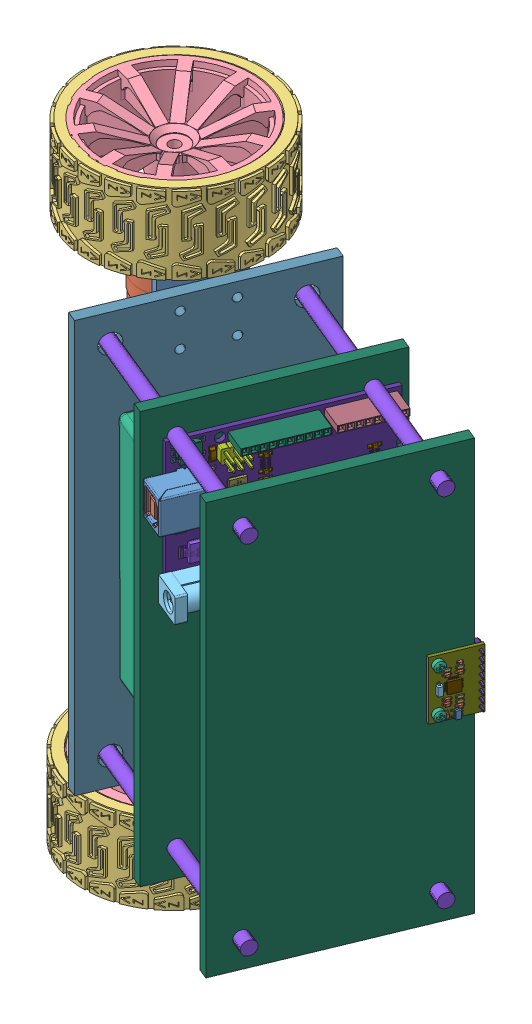
SolidWorks assembly Self-Balancing Robot, configuration Default. Lengths in mm.
Overall size (169.38 227.6 124.57).
147 component instances, 62 part files, 48 mates.
Components (placement in the parent):
- Motor Holder-3: Motor Holder [Default] at (-32.9879 122.7699 -70.1452) x (-0.380878 0 0.924625) z (0.924625 0 0.380878) size (26 33 33)
- Motor-3: Motor [Default] at (-47.7819 117.2699 -76.2392) x (0.924625 0 0.380878) z (0.380878 0 -0.924625) size (25 71 25)
- blue_wheel_with_adapter-1: blue_wheel_with_adapter [Default] at (-11.9395 117.0086 -118.8911) x (-0.932891 0 -0.360158) z (0 1 0) size (69.31 69.31 29.8)
  - 65mm tire-1: 65mm tire [Default] at (18.1044 52.2783 38.5614) x (-0.068419 0.997657 0) z (0 0 1) size (65.01 65.01 29)
  - blue_wheel_frame-2: blue_wheel_frame [Default] at (18.0756 52.6985 38.5614) x (0 0 -1) z (-0.994893 -0.10093 0) size (29 56 56)
  - motor_adapter-1: motor_adapter [Default] at (18.0661 52.7117 35.2614) x (0.583313 -0.812247 0) z (0 0 1) size (13.7 12 18.23)
- blue_wheel_with_adapter-2: blue_wheel_with_adapter [Default] at (-61.4059 -4.4687 -22.2185) x (-0.837844 0 -0.545909) z (0 -1 0) size (69.31 69.31 29.8)
  - 65mm tire-1: 65mm tire [Default] at (18.1044 52.2783 38.5614) x (-0.068419 0.997657 0) z (0 0 1) size (65.01 65.01 29)
  - blue_wheel_frame-2: blue_wheel_frame [Default] at (18.0756 52.6985 38.5614) x (0 0 -1) z (-0.994893 -0.10093 0) size (29 56 56)
  - motor_adapter-1: motor_adapter [Default] at (18.0661 52.7117 35.2614) x (0.583313 -0.812247 0) z (0 0 1) size (13.7 12 18.23)
- Motor-4: Motor [Default] at (-47.7819 -4.7301 -76.2392) x (0.924625 0 0.380878) z (-0.380878 0 0.924625) size (25 71 25)
- Motor Holder-4: Motor Holder [Default] at (-32.9879 -10.2301 -70.1452) x (0.380878 0 -0.924625) z (0.924625 0 0.380878) size (26 33 33)
- Battery-1: Battery [Default] at (-37.8979 90.6926 -146.4677) x (0.0011 -0.999996 -0.002671) z (-0.380877 -0.002889 0.924621) size (88 20.21 59.22)
  - battery_body-1: battery_body [Default] at (33.4598 40.6095 66.8775) size (85 20.21 55)
  - Mini Rocker 4-Pin Switch-1: Mini Rocker 4-Pin Switch [Default] at (67.6398 50.3895 39.3775) x (-1 0 0) z (0 -1 0) size (10.64 14.37 14.84)
  - dc_power_jack_assembly-1: dc_power_jack_assembly [Default] at (66.0649 52.0993 55.8301) x (1 0 0) z (0 0 -1) size (41 11.5 15)
    - main_body-1: main_body [Default] at (-16.1052 -4.2602 1.6818) size (34 11.5 15)
    - green_screw_section-1: green_screw_section [Default] at (-21.1052 -4.2602 6.6818) x (-1 0 0) z (0 0 -1) size (7 10 10)
    - jack_outer_metal-1: jack_outer_metal [Default] at (0.8948 1.4898 1.6818) x (0 0.735968 -0.677016) z (1 0 0) size (7 7 12)
    - jack_inner_rod-1: jack_inner_rod [Default] at (0.8948 1.4898 1.6818) x (0 0 -1) z (1 0 0) size (2.1 2.1 12)
    - wireholder_with_screw_assembly-1: wireholder_with_screw_assembly [Default] at (4.4628 17.1409 -69.445) x (0 0 -1) z (-1 0 0) size (4 9.26 5)
      - wireholder-1: wireholder [Default] at (-75.1268 12.4011 26.568) size (4 5.5 5)
      - pan cross head_ai-1: pan cross head_ai [CR-PHMS 0.06-80x0.125x0.125-N] at (-73.6268 21.1937 29.068) x (0 -1 0) z (0 0 1) size (4.26 2.95 2.95)
    - wireholder_with_screw_assembly-2: wireholder_with_screw_assembly [Default] at (4.4628 17.1409 -74.445) x (0 0 -1) z (-1 0 0) size (4 9.26 5)
      - wireholder-1: wireholder [Default] at (-75.1268 12.4011 26.568) size (4 5.5 5)
      - pan cross head_ai-1: pan cross head_ai [CR-PHMS 0.06-80x0.125x0.125-N] at (-73.6268 21.1937 29.068) x (0 -1 0) z (0 0 1) size (4.26 2.95 2.95)
- Base_0-1: Base_0 [Default] at (-26.5155 56.2699 -67.479) x (0 1 0) z (-0.380878 0 0.924625) size (150 4 75)
- Base_1-1: Base_1 [Default] at (14.168 56.2699 -50.7204) x (0 1 0) z (-0.380878 0 0.924625) size (150 4 75)
- L298N-1: L298N [Default] at (11.1248 21.059 -86.5942) x (0 -1 0) z (-0.380878 0 0.924625) size (39.39 19 41.67)
- Base_1-2: Base_1 [Default] at (54.8515 56.2699 -33.9617) x (0 1 0) z (-0.380878 0 0.924625) size (150 4 75)
- arduino uno.IGS-2: arduino uno.IGS [Default] at (3.8293 67.6059 -21.2898) x (0 -1 0) z (-0.380878 0 0.924625) size (60.05 15.26 75.79)
  - unoboard blue.IGS-1: unoboard blue.IGS [Default] at origin size (53.35 1.66 68.59)
  - 47uf CAP Dcase.IGS-1: 47uf CAP Dcase.IGS [Default] at (-9.4141 0 -18.4991) x (0 0 -1) z (1 0 0) size (7.21 5.88 8.01)
  - 47uf CAP Dcase.IGS-2: 47uf CAP Dcase.IGS [Default] at (-9.4141 0 -25.7132) x (0 0 -1) z (1 0 0) size (7.21 5.88 8.01)
  - USB SHELL.IGS-1: USB SHELL.IGS [Default] at (-38.02 0.43 6.35) size (13.73 15.21 16.52)
  - USB core.IGS-1: USB core.IGS [Default] at (-38.02 0.43 6.35) size (11.31 10.69 15.76)
  - usb top contact.IGS-1: usb top contact.IGS [Default] at (-36.77 6.52 5.97) size (1.01 9.68 13.77)
  - usb top contact.IGS-2: usb top contact.IGS [Default] at (-39.27 6.52 5.97) size (1.01 9.68 13.77)
  - usb btm contact.IGS-1: usb btm contact.IGS [Default] at (-36.77 4.84 5.97) size (1.14 6.85 11.77)
  - usb btm contact.IGS-2: usb btm contact.IGS [Default] at (-39.27 4.84 5.97) size (1.14 6.85 11.77)
  - power jack.IGS-1: power jack.IGS [Default] at (-7.675 0 1.905) size (11.21 15.21 15.91)
  - crystal.IGS-1: crystal.IGS [Default] at (-26.162 0 -18.923) x (1 0 0) z (0 0 -1) size (4.01 5.08 12.71)
  - 2pin_header__02.IGS-1: 2pin_header__02.IGS [Default] at (-46.23 0 -15.75) size (5.01 11.76 2.55)
  - 2pin_header__02.IGS-2: 2pin_header__02.IGS [Default] at (-30.43 0 -64.91) x (0 0 1) z (-1 0 0) size (5.01 11.76 2.55)
  - 2pin_header__02.IGS-3: 2pin_header__02.IGS [Default] at (-27.89 0 -64.91) x (0 0 1) z (-1 0 0) size (5.01 11.76 2.55)
  - 2pin_header__02.IGS-4: 2pin_header__02.IGS [Default] at (-25.35 0 -64.91) x (0 0 1) z (-1 0 0) size (5.01 11.76 2.55)
  - 2pin_header__02.IGS-5: 2pin_header__02.IGS [Default] at (-46.23 0 -18.29) size (5.01 11.76 2.55)
  - 2pin_header__02.IGS-6: 2pin_header__02.IGS [Default] at (-46.23 0 -20.83) size (5.01 11.76 2.55)
  - nano - reg.IGS-1: nano - reg.IGS [Default] at (-17.399 0 -7.747) size (6.51 1.75 8.31)
  - led.IGS-1: led.IGS [Default] at (-34.29 0 -27.94) x (0 0 1) z (-1 0 0) size (4.01 0.86 1.55)
  - led.IGS-2: led.IGS [Default] at (-36.83 0 -27.94) x (0 0 1) z (-1 0 0) size (4.01 0.86 1.55)
  - led.IGS-3: led.IGS [Default] at (-42.037 0 -27.94) x (0 0 1) z (-1 0 0) size (4.01 0.86 1.55)
  - led.IGS-4: led.IGS [Default] at (-36.576 0 -58.42) x (0 0 1) z (-1 0 0) size (4.01 0.86 1.55)
  - dip28.IGS-1: dip28.IGS [Default] at (-16.383 1.5 -46.355) x (0 0 -1) z (1 0 0) size (35.49 2.81 10.11)
  - dip socket pin.IGS-1: dip socket pin.IGS [Default] at (-20.193 4.3 -62.865) x (0 0 -1) z (1 0 0) size (1.71 7.38 1.71)
  - dip socket pin.IGS-2: dip socket pin.IGS [Default] at (-12.573 4.3 -62.865) x (0 0 -1) z (1 0 0) size (1.71 7.38 1.71)
  - dip socket pin.IGS-3: dip socket pin.IGS [Default] at (-20.193 4.3 -60.325) x (0 0 -1) z (1 0 0) size (1.71 7.38 1.71)
  - dip socket pin.IGS-4: dip socket pin.IGS [Default] at (-12.573 4.3 -60.325) x (0 0 -1) z (1 0 0) size (1.71 7.38 1.71)
  - dip socket pin.IGS-5: dip socket pin.IGS [Default] at (-20.193 4.3 -57.785) x (0 0 -1) z (1 0 0) size (1.71 7.38 1.71)
  - dip socket pin.IGS-6: dip socket pin.IGS [Default] at (-12.573 4.3 -57.785) x (0 0 -1) z (1 0 0) size (1.71 7.38 1.71)
  - dip socket pin.IGS-7: dip socket pin.IGS [Default] at (-20.193 4.3 -55.245) x (0 0 -1) z (1 0 0) size (1.71 7.38 1.71)
  - dip socket pin.IGS-8: dip socket pin.IGS [Default] at (-12.573 4.3 -55.245) x (0 0 -1) z (1 0 0) size (1.71 7.38 1.71)
  - dip socket pin.IGS-9: dip socket pin.IGS [Default] at (-20.193 4.3 -52.705) x (0 0 -1) z (1 0 0) size (1.71 7.38 1.71)
  - dip socket pin.IGS-10: dip socket pin.IGS [Default] at (-12.573 4.3 -52.705) x (0 0 -1) z (1 0 0) size (1.71 7.38 1.71)
  - dip socket pin.IGS-11: dip socket pin.IGS [Default] at (-20.193 4.3 -50.165) x (0 0 -1) z (1 0 0) size (1.71 7.38 1.71)
  - dip socket pin.IGS-12: dip socket pin.IGS [Default] at (-12.573 4.3 -50.165) x (0 0 -1) z (1 0 0) size (1.71 7.38 1.71)
  - dip socket pin.IGS-13: dip socket pin.IGS [Default] at (-20.193 4.3 -47.625) x (0 0 -1) z (1 0 0) size (1.71 7.38 1.71)
  - dip socket pin.IGS-14: dip socket pin.IGS [Default] at (-12.573 4.3 -47.625) x (0 0 -1) z (1 0 0) size (1.71 7.38 1.71)
  - dip socket pin.IGS-15: dip socket pin.IGS [Default] at (-20.193 4.3 -45.085) x (0 0 -1) z (1 0 0) size (1.71 7.38 1.71)
  - dip socket pin.IGS-16: dip socket pin.IGS [Default] at (-12.573 4.3 -45.085) x (0 0 -1) z (1 0 0) size (1.71 7.38 1.71)
  - dip socket pin.IGS-17: dip socket pin.IGS [Default] at (-20.193 4.3 -42.545) x (0 0 -1) z (1 0 0) size (1.71 7.38 1.71)
  - dip socket pin.IGS-18: dip socket pin.IGS [Default] at (-12.573 4.3 -42.545) x (0 0 -1) z (1 0 0) size (1.71 7.38 1.71)
  - dip socket pin.IGS-19: dip socket pin.IGS [Default] at (-20.193 4.3 -40.005) x (0 0 -1) z (1 0 0) size (1.71 7.38 1.71)
  - dip socket pin.IGS-20: dip socket pin.IGS [Default] at (-12.573 4.3 -40.005) x (0 0 -1) z (1 0 0) size (1.71 7.38 1.71)
  - dip socket pin.IGS-21: dip socket pin.IGS [Default] at (-20.193 4.3 -37.465) x (0 0 -1) z (1 0 0) size (1.71 7.38 1.71)
  - dip socket pin.IGS-22: dip socket pin.IGS [Default] at (-12.573 4.3 -37.465) x (0 0 -1) z (1 0 0) size (1.71 7.38 1.71)
  - dip socket pin.IGS-23: dip socket pin.IGS [Default] at (-20.193 4.3 -34.925) x (0 0 -1) z (1 0 0) size (1.71 7.38 1.71)
  - dip socket pin.IGS-24: dip socket pin.IGS [Default] at (-12.573 4.3 -34.925) x (0 0 -1) z (1 0 0) size (1.71 7.38 1.71)
  - dip socket pin.IGS-25: dip socket pin.IGS [Default] at (-20.193 4.3 -32.385) x (0 0 -1) z (1 0 0) size (1.71 7.38 1.71)
  - dip socket pin.IGS-26: dip socket pin.IGS [Default] at (-12.573 4.3 -32.385) x (0 0 -1) z (1 0 0) size (1.71 7.38 1.71)
  - dip socket pin.IGS-27: dip socket pin.IGS [Default] at (-20.193 4.3 -29.845) x (0 0 -1) z (1 0 0) size (1.71 7.38 1.71)
  - dip socket pin.IGS-28: dip socket pin.IGS [Default] at (-12.573 4.3 -29.845) x (0 0 -1) z (1 0 0) size (1.71 7.38 1.71)
  - atmega16u2.IGS-1: atmega16u2.IGS [Default] at (-34.671 0.06 -20) x (1 0 0) z (0 0 -1) size (5.51 1.16 5.51)
  - 8 PORT HEADER.IGS-1: 8 PORT HEADER.IGS [Default] at (-50.8 0 -45.72) x (0 0 -1) z (1 0 0) size (20.33 10.52 2.42)
  - 8 PORT HEADER.IGS-2: 8 PORT HEADER.IGS [Default] at (-2.54 0 -27.94) x (0 0 -1) z (1 0 0) size (20.33 10.52 2.42)
  - 6 PORT HEADER.IGS-1: 6 PORT HEADER.IGS [Default] at (-2.54 0 -50.8) x (0 0 -1) z (1 0 0) size (15.25 10.52 2.42)
  - 10 PORT HEADER.IGS-1: 10 PORT HEADER.IGS [Default] at (-50.8 0 -18.796) x (0 0 -1) z (1 0 0) size (25.41 10.52 2.42)
  - ATMEL328P.IGS-1: ATMEL328P.IGS [Default] at (-16.383 4.3 -46.355) x (0 0 -1) z (1 0 0) size (35.01 7.35 7.88)
  - 102 RESISTOR PACK.IGS-1: 102 RESISTOR PACK.IGS [Default] at (-33.782 0 -58.42) size (3.21 0.54 3.01)
  - 102 RESISTOR PACK.IGS-2: 102 RESISTOR PACK.IGS [Default] at (-39.37 0 -27.94) size (3.21 0.54 3.01)
  - 103 RESISTOR PACK.IGS-1: 103 RESISTOR PACK.IGS [Default] at (-23.876 0 -27.94) size (3.21 0.55 3.01)
  - 220 RESISTOR PACK.IGS-1: 220 RESISTOR PACK.IGS [Default] at (-36.83 0 -12.827) size (3.21 0.54 3.01)
  - 16mhz crystal - measured.IGS-1: 16mhz crystal - measured.IGS [Default] at (-24.892 0 -41.275) x (0 0 -1) z (1 0 0) size (3.41 0.81 2.01)
  - PADS001.IGS-1: PADS001.IGS [Default] at (-39.878 0.1 -18.288) x (-1 0 0) z (0 0 1) size (4.57 0.13 4.59)
  - 603 cap on pad.IGS-1: 603 cap on pad.IGS [Default] at (-44.45 0 -27.94) x (0 0 -1) z (1 0 0) size (2.77 0.91 1.03)
  - 603 cap on pad.IGS-2: 603 cap on pad.IGS [Default] at (-29.845 0 -27.94) x (0 0 -1) z (1 0 0) size (2.77 0.91 1.03)
  - 603 cap on pad.IGS-3: 603 cap on pad.IGS [Default] at (-31.496 0 -27.94) x (0 0 -1) z (1 0 0) size (2.77 0.91 1.03)
  - 603 cap on pad.IGS-4: 603 cap on pad.IGS [Default] at (-15.24 0 -18.415) size (2.77 0.91 1.03)
  - 603 cap on pad.IGS-5: 603 cap on pad.IGS [Default] at (-29.845 0 -12.065) x (0 0 1) z (-1 0 0) size (2.77 0.91 1.03)
  - 603 cap on pad.IGS-6: 603 cap on pad.IGS [Default] at (-29.591 0 -22.352) x (0 0 1) z (-1 0 0) size (2.77 0.91 1.03)
  - 603 cap on pad.IGS-7: 603 cap on pad.IGS [Default] at (-29.591 0 -16.002) x (0 0 1) z (-1 0 0) size (2.77 0.91 1.03)
  - 603 cap on pad.IGS-8: 603 cap on pad.IGS [Default] at (-41.91 0 -12.7) x (0 0 1) z (-1 0 0) size (2.77 0.91 1.03)
  - ssot3.IGS-1: ssot3.IGS [Default] at (-26.5 0 -8.128) x (-1 0 0) z (0 0 -1) size (3.01 1.14 3.1)
  - mf-msmf050-2.IGS-1: mf-msmf050-2.IGS [Default] at (-26.5 0 -4.064) size (5.76 1.08 3.73)
  - lmv358.IGS-1: lmv358.IGS [Default] at (-15.24 0 -21.971) x (0 0 -1) z (1 0 0) size (3.71 1.41 2.91)
  - lp2985dgkr.IGS-1: lp2985dgkr.IGS [Default] at (-20.32 0 -19.05) x (0 0 -1) z (1 0 0) size (5.86 1.11 3.01)
  - cd1206 diode.IGS-1: cd1206 diode.IGS [Default] at (-27.94 0 -59.436) x (0 0 -1) z (1 0 0) size (2.03 1.02 5.01)
  - cd1206 diode.IGS-2: cd1206 diode.IGS [Default] at (-46.228 0 -13.081) x (0 0 1) z (-1 0 0) size (2.03 1.02 5.01)
  - 603 resistor.IGS-1: 603 resistor.IGS [Default] at (-29.591 0 -19.05) x (0 0 1) z (-1 0 0) size (2.37 0.71 1.03)
  - blm21.IGS-1: blm21.IGS [Default] at (-45.085 0 -7.62) x (0 0 -1) z (1 0 0) size (2.78 0.96 1.32)
  - m7 diode.IGS-1: m7 diode.IGS [Default] at (-2.794 0 -21.59) x (0 0 -1) z (1 0 0) size (6.67 2.45 2.51)
  - MLC0603.IGS-1: MLC0603.IGS [Default] at (-33.655 0 -12.827) x (0 0 -1) z (1 0 0) size (2.37 0.62 1.03)
  - MLC0603.IGS-2: MLC0603.IGS [Default] at (-39.37 0 -12.827) x (0 0 -1) z (1 0 0) size (2.37 0.62 1.03)
  - RESET CORE.IGS-1: RESET CORE.IGS [Default] at (-49.403 0.1 -6.35) x (-1 0 0) z (0 0 -1) size (6.21 3.11 9.61)
  - RESET.IGS-1: RESET.IGS [Default] at (-49.403 0.1 -6.35) x (0 0 1) z (-1 0 0) size (7.31 2.01 6.22)
- MPU 6050 IMU-1: MPU 6050 IMU [Default] at (63.7627 63.0726 -82.8654) x (0 -1 0) z (-0.380878 0 0.924625) size (21.11 11.18 15.88)
  - Base-1: Base [Default] at (7.2489 10.9584 16.5726) size (21.11 1.14 15.75)
  - pin header-1: pin header [Default] at (16.0246 10.3869 9.8416) x (-1 0 0) z (0 0 1) size (2.54 11.18 2.54)
  - pin header-2: pin header [Default] at (13.4846 10.3869 9.8416) x (-1 0 0) z (0 0 1) size (2.54 11.18 2.54)
  - pin header-3: pin header [Default] at (10.9446 10.3869 9.8416) x (-1 0 0) z (0 0 1) size (2.54 11.18 2.54)
  - pin header-4: pin header [Default] at (8.4046 10.3869 9.8416) x (-1 0 0) z (0 0 1) size (2.54 11.18 2.54)
  - pin header-5: pin header [Default] at (5.8646 10.3869 9.8416) x (-1 0 0) z (0 0 1) size (2.54 11.18 2.54)
  - pin header-6: pin header [Default] at (3.3246 10.3869 9.8416) x (-1 0 0) z (0 0 1) size (2.54 11.18 2.54)
  - pin header-7: pin header [Default] at (0.7846 10.3869 9.8416) x (-1 0 0) z (0 0 1) size (2.54 11.18 2.54)
  - pin header-8: pin header [Default] at (-1.7554 10.3869 9.8416) x (-1 0 0) z (0 0 1) size (2.54 11.18 2.54)
  - sensor chip-1: sensor chip [Default] at (7.2489 11.5499 17.4466) size (5.4 0.9 5.4)
  - S2NH chip-1: S2NH chip [Default] at (16.1026 12.3799 16.5726) size (3 1.35 3.65)
  - Resistor small-3: Resistor small [Default] at (16.1026 11.5314 19.3726) size (2.75 0.99 1)
  - Resistor small-4: Resistor small [Default] at (13.9776 11.5314 15.6976) x (0 0 -1) z (1 0 0) size (2.75 0.99 1)
  - Resistor small black-3: Resistor small black [Default] at (12.6276 11.5299 15.6976) x (0 0 1) z (-1 0 0) size (2.45 0.6 1.02)
  - Resistor small black-4: Resistor small black [Default] at (11.1276 11.5299 15.6976) x (0 0 1) z (-1 0 0) size (2.45 0.6 1.02)
  - Resistor small-5: Resistor small [Default] at (12.6276 11.5314 19.3216) x (0 0 -1) z (1 0 0) size (2.75 0.99 1)
  - Resistor small-6: Resistor small [Default] at (11.1276 11.5314 19.3216) x (0 0 -1) z (1 0 0) size (2.75 0.99 1)
  - Resistor small-7: Resistor small [Default] at (3.3702 11.5314 19.3216) x (0 0 -1) z (1 0 0) size (2.75 0.99 1)
  - Resistor small black-5: Resistor small black [Default] at (1.8702 11.5299 15.6972) x (0 0 -1) z (1 0 0) size (2.45 0.6 1.02)
  - Resistor small-8: Resistor small [Default] at (3.3702 11.5314 15.6976) x (0 0 1) z (-1 0 0) size (2.75 0.99 1)
  - Small LED-1: Small LED [Default] at (0.3652 11.5299 15.6976) size (0.85 0.84 1.9)
  - Resistor small black-6: Resistor small black [Default] at (1.8702 11.5299 19.3216) x (0 0 1) z (-1 0 0) size (2.45 0.6 1.02)
  - Resistor black-1: Resistor black [Default] at (7.2489 12.3799 21.6466) size (4.2 1.6 1.6)
- fillister head screw_ai-1: fillister head screw_ai [CR-FIMS 0.086-64x0.3125x0.3125-N] at (68.0653 48.0449 -57.5036) x (-0.924625 0 -0.380878) z (0.380878 0 -0.924625) size (10.02 3.56 3.56)
- fillister head screw_ai-2: fillister head screw_ai [CR-FIMS 0.086-64x0.3125x0.3125-N] at (68.0653 63.6024 -57.5036) x (-0.924625 0 -0.380878) z (0.380878 0 -0.924625) size (10.02 3.56 3.56)
- machine screw nut hex_ai2-2: machine screw nut hex_ai2 [MSHXNUT 0.086-56-S-N] at (61.3574 48.0449 -60.2667) x (0.380878 0 -0.924625) z (0.924625 0 0.380878) size (4.78 5.51 1.68)
- machine screw nut hex_ai2-3: machine screw nut hex_ai2 [MSHXNUT 0.086-56-S-N] at (61.3606 63.6024 -60.2654) x (0.380878 0 -0.924625) z (0.924625 0 0.380878) size (4.78 5.51 1.68)
- Structure holder-1: Structure holder [Default] at (49.0005 -8.7301 -6.6301) x (0.380878 0 -0.924625) z (0 1 0) size (5 102 5)
- Structure holder-2: Structure holder [Default] at (69.9488 121.2699 -57.4845) x (0.370863 -0.227816 -0.900311) z (0.08677 0.973704 -0.210644) size (5 102 5)
- Structure holder-3: Structure holder [Default] at (69.9488 -8.7301 -57.4845) x (0.380878 0 -0.924625) z (0 1 0) size (5 102 5)
- Structure holder-4: Structure holder [Default] at (49.0005 121.2699 -6.6301) x (0.380878 0 -0.924625) z (0 1 0) size (5 102 5)
Mates (geometry in assembly coordinates):
- Coincident6: coincident anti-aligned: cylinder of Motor Holder-3 through (-44.7349 139.2699 -83.6362) axis (0 -1 0) radius 1.5; circle of Motor-3
- Coincident7: coincident anti-aligned: plane of Motor Holder-3 through (-65.6781 136.2699 -69.5514) normal (0 -1 0); plane of Motor-3 through (-47.7819 136.2699 -76.2392) normal (0 1 0)
- Concentric4: concentric aligned: circle of Motor Holder-3; circle of Motor-3
- Concentric6: concentric aligned: cylinder of Motor-3 through (-47.7819 148.2699 -76.2392) axis (0 -1 0) radius 2; cylinder of blue_wheel_with_adapter-1/motor_adapter-1 through (-47.7819 152.2699 -76.2392) axis (0 -1 0) radius 3
- Distance1: distance = 1 mm anti-aligned: plane of Motor Holder-3 through (-25.2626 139.2699 -81.0227) normal (0 1 0); plane of blue_wheel_with_adapter-1/motor_adapter-1 through (-47.7778 140.2699 -76.2235) normal (0 -1 0)
- Concentric7: concentric aligned: cylinder of blue_wheel_with_adapter-2/motor_adapter-1 through (-47.7819 -39.7301 -76.2392) axis (0 1 0) radius 3; cylinder of Motor-4 through (-47.7819 -35.7301 -76.2392) axis (0 1 0) radius 2
- Concentric8: concentric aligned: circle of Motor-4; circle of Motor Holder-4
- Coincident12: coincident anti-aligned: circle of Motor-4; cylinder of Motor Holder-4 through (-50.8289 -26.7301 -68.8422) axis (0 1 0) radius 1.5
- Coincident13: coincident anti-aligned: plane of Motor-4 through (-47.7819 -23.7301 -76.2392) normal (0 -1 0); plane of Motor Holder-4 through (-55.7752 -23.7301 -93.5916) normal (0 1 0)
- Distance2: distance = 1 mm anti-aligned: plane of Motor Holder-4 through (-35.1654 -26.7301 -56.9824) normal (0 -1 0); plane of blue_wheel_with_adapter-2/motor_adapter-1 through (-47.7667 -27.7301 -76.2451) normal (0 1 0)
- Concentric9: concentric anti-aligned: cylinder of Motor-3 through (-47.7819 77.2699 -76.2392) axis (0 1 0) radius 7; cylinder of Motor-4 through (-47.7819 35.2699 -76.2392) axis (0 -1 0) radius 7
- Coincident15: coincident aligned: plane of Motor Holder-3 through (-30.214 122.7699 -69.0025) normal (0.924625 0 0.380878); plane of Motor Holder-4 through (-30.214 -10.2301 -69.0025) normal (0.924625 0 0.380878)
- Parallel1: parallel anti-aligned: plane of Motor Holder-4 through (-30.214 -10.2301 -69.0025) normal (0.924625 0 0.380878); plane of Battery-1/battery_body-1 through (-25.7846 57.0398 -69.2535) normal (-0.924625 0 -0.380878)
- Parallel2: parallel anti-aligned: plane of blue_wheel_with_adapter-2/65mm tire-1 through (-48.0354 -57.5301 -75.9029) normal (0 -1 0)
- Coincident16: coincident anti-aligned: plane of Motor Holder-3 through (-30.214 122.7699 -69.0025) normal (0.924625 0 0.380878); plane of Base_0-1 through (-30.214 56.2699 -69.0025) normal (-0.924625 0 -0.380878)
- Concentric10: concentric anti-aligned: cylinder of Motor Holder-4 through (-27.167 -13.7301 -76.3995) axis (-0.924625 0 -0.380878) radius 1.5; cylinder of Base_0-1 through (-27.167 -13.7301 -76.3995) axis (0.924625 0 0.380878) radius 1.5
- Concentric12: concentric anti-aligned: cylinder of Motor Holder-4 through (-33.261 -13.7301 -61.6055) axis (-0.924625 0 -0.380878) radius 1.5; cylinder of Base_0-1 through (-33.261 -13.7301 -61.6055) axis (0.924625 0 0.380878) radius 1.5
- Concentric13: concentric anti-aligned: cylinder of Motor Holder-3 through (-33.261 126.2699 -61.6055) axis (-0.924625 0 -0.380878) radius 1.5; cylinder of Base_0-1 through (-33.261 126.2699 -61.6055) axis (0.924625 0 0.380878) radius 1.5
- Coincident17: coincident anti-aligned: plane of Battery-1/battery_body-1 through (-25.7846 57.0398 -69.2535) normal (-0.924625 0 -0.380878); plane of Base_0-1 through (-26.5155 56.2699 -67.479) normal (0.924625 0 0.380878)
- Distance3: distance = 40 mm anti-aligned: plane of Base_0-1 through (-26.5155 56.2699 -67.479) normal (0.924625 0 0.380878); plane of Base_1-1 through (10.4695 56.2699 -52.2439) normal (-0.924625 0 -0.380878)
- Coincident19: coincident anti-aligned: plane of Base_1-1 through (14.168 56.2699 -50.7204) normal (0.924625 0 0.380878); plane of L298N-1 through (21.4847 27.9791 -68.4826) normal (-0.924625 0 -0.380878)
- Parallel4: parallel aligned: plane of Base_1-1 through (24.7524 -18.7301 -86.9173) normal (0.380878 0 -0.924625); plane of L298N-1 through (23.1711 -7.4118 -69.951) normal (0.380878 0 -0.924625)
- Concentric16: concentric aligned: cylinder of Base_1-1 through (20.9437 -8.7301 -77.6711) axis (0.924625 0 0.380878) radius 2.5; cylinder of Base_1-2 through (61.6272 -8.7301 -60.9124) axis (0.924625 0 0.380878) radius 2.5
- Concentric17: concentric aligned: cylinder of Base_1-1 through (-0.0047 -8.7301 -26.8167) axis (0.924625 0 0.380878) radius 2.5; cylinder of Base_1-2 through (40.6789 -8.7301 -10.058) axis (0.924625 0 0.380878) radius 2.5
- Distance5: distance = 40 mm anti-aligned: plane of Base_1-2 through (51.153 56.2699 -35.4852) normal (-0.924625 0 -0.380878); plane of Base_1-1 through (14.168 56.2699 -50.7204) normal (0.924625 0 0.380878)
- Coincident20: coincident anti-aligned: plane of Base_1-2 through (54.8515 56.2699 -33.9617) normal (0.924625 0 0.380878); plane of MPU 6050 IMU-1/Base-1 through (67.0545 55.8236 -63.5858) normal (-0.924625 0 -0.380878)
- Parallel6: parallel aligned: plane of Base_1-2 through (36.8701 -18.7301 -0.8118) normal (-0.380878 0 0.924625); plane of MPU 6050 IMU-1/Base-1 through (65.1123 66.3773 -55.8699) normal (-0.380878 0 0.924625)
- Coincident26: coincident anti-aligned: plane of Base_1-2 through (65.4359 -18.7301 -70.1587) normal (0.380878 0 -0.924625); plane of MPU 6050 IMU-1/pin header-1 through (66.7859 46.4129 -69.6026) normal (-0.380878 0 0.924625)
- Distance7: distance = 64 mm aligned: plane of Base_1-2 through (36.8701 -18.7301 -0.8118) normal (0 -1 0); plane of MPU 6050 IMU-1/Base-1 through (65.1123 45.2699 -55.8699) normal (0 -1 0)
- Concentric20: concentric anti-aligned: cylinder of MPU 6050 IMU-1/Base-1 through (66.116 48.0449 -58.3066) axis (-0.924625 0 -0.380878) radius 1.5557; cylinder of fillister head screw_ai-1 through (91.5508 48.0449 -47.8293) axis (0.924625 0 0.380878) radius 1.778
- Coincident29: coincident anti-aligned: plane of MPU 6050 IMU-1/Base-1 through (68.1113 55.8236 -63.1504) normal (0.924625 0 0.380878); plane of fillister head screw_ai-1 through (66.116 49.1371 -58.3066) normal (-0.924625 0 -0.380878)
- Concentric21: concentric anti-aligned: cylinder of MPU 6050 IMU-1/Base-1 through (66.116 63.6024 -58.3066) axis (-0.924625 0 -0.380878) radius 1.5557; cylinder of fillister head screw_ai-2 through (91.5508 63.6024 -47.8293) axis (0.924625 0 0.380878) radius 1.778
- Coincident30: coincident anti-aligned: plane of MPU 6050 IMU-1/Base-1 through (68.1113 55.8236 -63.1504) normal (0.924625 0 0.380878); plane of fillister head screw_ai-2 through (66.116 64.6946 -58.3066) normal (-0.924625 0 -0.380878)
- Tangent1: tangent anti-aligned: plane of Base_1-1 through (14.168 56.2699 -50.7204) normal (0.924625 0 0.380878); face of arduino uno.IGS-2/unoboard blue.IGS-1
- Tangent2: tangent aligned: plane of Base_1-1 through (-3.8134 -18.7301 -17.5704) normal (-0.380878 0 0.924625); edge_curve of ?
- Concentric23: concentric aligned: cylinder of fillister head screw_ai-1 through (91.5508 48.0449 -47.8293) axis (0.924625 0 0.380878) radius 1.0922; cylinder of machine screw nut hex_ai2-2 through (38.2071 48.0449 -69.803) axis (0.924625 0 0.380878) radius 1.0922
- Concentric24: concentric aligned: cylinder of fillister head screw_ai-2 through (91.5508 63.6024 -47.8293) axis (0.924625 0 0.380878) radius 1.0922; cylinder of machine screw nut hex_ai2-3 through (59.8106 63.6024 -60.9039) axis (0.924625 0 0.380878) radius 0.889
- Coincident34: coincident anti-aligned: plane of Base_1-2 through (51.153 56.2699 -35.4852) normal (-0.924625 0 -0.380878); plane of machine screw nut hex_ai2-3 through (61.3606 66.3594 -60.2654) normal (0.924625 0 0.380878)
- Concentric26: concentric aligned: cylinder of Base_1-2 through (40.6789 -8.7301 -10.058) axis (0.924625 0 0.380878) radius 2.5; cylinder of Structure holder-1 through (-45.3113 -8.7301 -45.4797) axis (0.924625 0 0.380878) radius 2.5
- Distance8: distance = 5 mm aligned: plane of Structure holder-1 through (49.0005 -8.7301 -6.6301) normal (0.924625 0 0.380878); plane of Base_1-2 through (54.8515 56.2699 -33.9617) normal (0.924625 0 0.380878)
- Concentric27: concentric aligned: cylinder of Base_1-2 through (61.6272 -8.7301 -60.9124) axis (0.924625 0 0.380878) radius 2.5; cylinder of Structure holder-3 through (-24.363 -8.7301 -96.3341) axis (0.924625 0 0.380878) radius 2.5
- Distance9: distance = 5 mm aligned: plane of Base_1-2 through (54.8515 56.2699 -33.9617) normal (0.924625 0 0.380878); plane of Structure holder-3 through (69.9488 -8.7301 -57.4845) normal (0.924625 0 0.380878)
- Concentric28: concentric aligned: cylinder of Base_1-2 through (40.6789 121.2699 -10.058) axis (0.924625 0 0.380878) radius 2.5; cylinder of Structure holder-4 through (-45.3113 121.2699 -45.4797) axis (0.924625 0 0.380878) radius 2.5
- Distance10: distance = 5 mm aligned: plane of Structure holder-4 through (49.0005 121.2699 -6.6301) normal (0.924625 0 0.380878); plane of Base_1-2 through (54.8515 56.2699 -33.9617) normal (0.924625 0 0.380878)
- Concentric29: concentric anti-aligned: circle of Base_1-2; cylinder of Structure holder-2 through (-24.363 121.2699 -96.3341) axis (0.924625 0 0.380878) radius 2.5
- Distance11: distance = 5 mm aligned: plane of Structure holder-2 through (69.9488 121.2699 -57.4845) normal (0.924625 0 0.380878); plane of Base_1-2 through (54.8515 56.2699 -33.9617) normal (0.924625 0 0.380878)
- Concentric30: concentric aligned: cylinder of Base_0-1 through (-40.6882 121.2699 -43.5753) axis (0.924625 0 0.380878) radius 3.5226; cylinder of Structure holder-4 through (-45.3113 121.2699 -45.4797) axis (0.924625 0 0.380878) radius 2.5
- Concentric31: concentric aligned: cylinder of Base_0-1 through (-19.7399 121.2699 -94.4297) axis (0.924625 0 0.380878) radius 3.5226; cylinder of Structure holder-2 through (-24.363 121.2699 -96.3341) axis (0.924625 0 0.380878) radius 2.5
